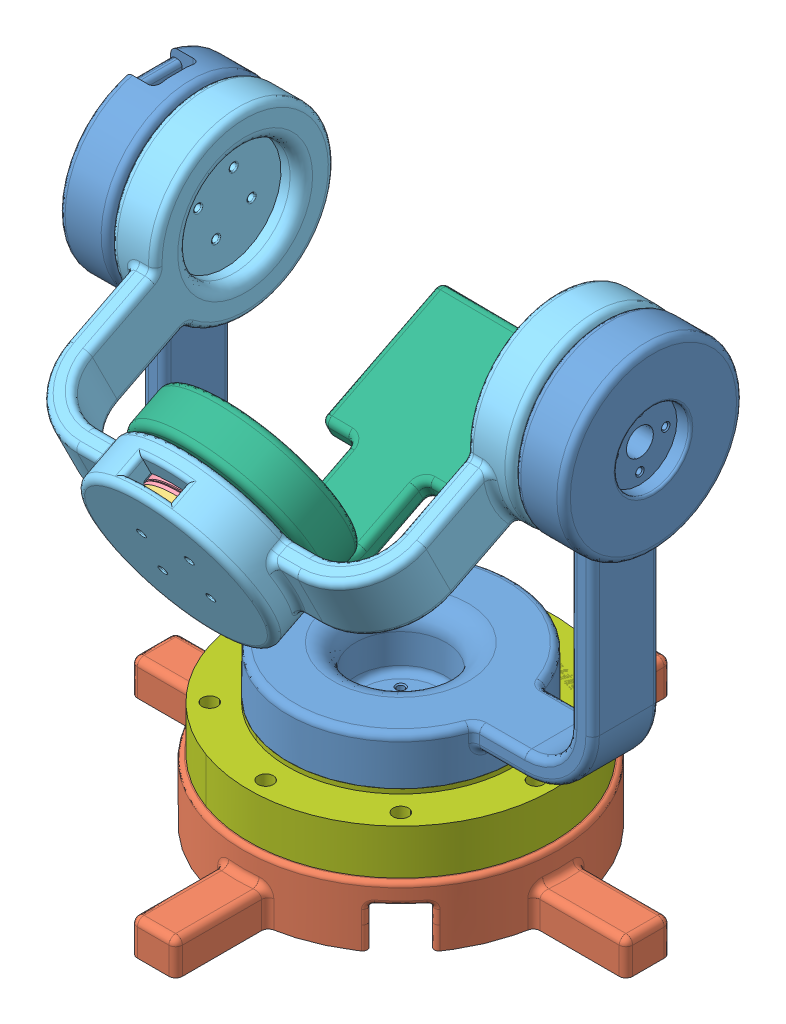
SolidWorks assembly 三轴转台, configuration 默认. Lengths in mm.
Overall size (300.48 271.26 300.48).
11 component instances, 7 part files, 26 mates.
Components (placement in the parent):
- 第一连接臂-1: 第一连接臂 [默认] at (-199.9775 0.5384 135.9766) x (-0.705804 0 0.708407) z (-0.708407 0 -0.705804) size (212.48 206 212.48)
- 转台底座-1: 转台底座 [默认] at (-199.9775 -45.4616 135.9766) size (220 27 220)
- 电机后盖.STEP-2: 电机后盖.STEP [默认] at (-306.9773 144.5384 136.1736) x (0.999998 0 -0.001841) z (0.001841 0 0.999998) size (7 49 49)
- 电机转子.STEP-2: 电机转子.STEP [默认] at (-282.9774 144.5384 136.1294) x (-0.999998 0 0.001841) z (-0.000828 -0.892998 -0.450059) size (19 49 49)
- 第二连接臂-1: 第二连接臂 [默认] at (-282.9774 144.5384 136.1294) x (0.000576 -0.949686 0.313204) z (0.001748 0.313204 0.949684) size (146.24 178 146.24)
- 电机后盖.STEP-3: 电机后盖.STEP [默认] at (-199.8016 96.3819 231.5273) x (-0.001644 0.45006 -0.892997) z (0.661169 -0.66947 -0.338622) size (7 49 49)
- 电机转子.STEP-3: 电机转子.STEP [默认] at (-199.8411 107.1834 210.0953) x (0.001644 -0.45006 0.892997) z (-0.99954 0.026307 0.015098) size (19 49 49)
- 第三连接臂-1: 第三连接臂 [默认] at (-199.8411 107.1834 210.0953) x (-0.728198 -0.612569 -0.307388) z (0.685365 -0.649773 -0.32874) size (102.4 119 102.4)
- 3264716736010.10.100(1).step-1: 3264716736010.10.100(1).step [默认] at (-199.9775 -28.4616 135.9766) x (0.939693 0 0.34202) z (-0.34202 0 0.939693) size (135 22 135)
- 电机后盖.STEP-4: 电机后盖.STEP [默认] at (-199.9775 -45.4616 135.9766) x (0 1 0) z (0.707107 0 -0.707107) size (7 49 49)
- 电机转子.STEP-4: 电机转子.STEP [默认] at (-199.9775 -21.4616 135.9766) x (0 -1 0) z (0.999998 0 -0.001841) size (19 49 49)
Mates (geometry in assembly coordinates):
- 重合9: coincident anti-aligned: plane of 第一连接臂-1 through (-306.9773 0.5384 136.1736) normal (0.999998 0 -0.001841); plane of 电机后盖.STEP-2 through (-306.9773 154.2384 136.1736) normal (-0.999998 0 0.001841)
- 同心7: concentric aligned: cylinder of 第一连接臂-1 through (-306.9773 144.5384 136.1736) axis (0.999998 0 -0.001841) radius 25; cylinder of 电机后盖.STEP-2 through (-299.1523 144.5384 136.1592) axis (0.999998 0 -0.001841) radius 22.5
- 平行4: parallel: line of 第一连接臂-1 through (-302.9589 168.5384 146.1662) axis (0 1 0); plane of 电机后盖.STEP-2 through (-300.9681 171.6257 141.1625) normal (-0.001841 0 -0.999998)
- 重合11: coincident anti-aligned: plane of 电机后盖.STEP-2 through (-299.9773 168.0384 136.1607) normal (0.999998 0 -0.001841); plane of 电机转子.STEP-2 through (-300.016 155.1148 115.1753) normal (-0.999998 0 0.001841)
- 同心8: concentric aligned: cylinder of 电机后盖.STEP-2 through (-299.1523 144.5384 136.1592) axis (0.999998 0 -0.001841) radius 22.5; cylinder of 电机转子.STEP-2 through (-278.5781 144.5384 136.1213) axis (0.999998 0 -0.001841) radius 24.5
- 重合13: coincident anti-aligned: plane of 电机转子.STEP-2 through (-282.9877 147.3738 130.5035) normal (0.999998 0 -0.001841); plane of 第二连接臂-1 through (-282.9774 144.5384 136.1294) normal (-0.999998 0 0.001841)
- 同心11: concentric anti-aligned: cylinder of 电机转子.STEP-2 through (-285.9555 148.4534 148.006) axis (0.999998 0 -0.001841) radius 1.25; cylinder of 第二连接臂-1 through (-272.9555 148.4534 147.982) axis (-0.999998 0 0.001841) radius 1.6
- 同心12: concentric anti-aligned: cylinder of 电机转子.STEP-2 through (-285.9992 140.6233 124.2639) axis (0.999998 0 -0.001841) radius 1.25; cylinder of 第二连接臂-1 through (-272.9992 140.6233 124.2399) axis (-0.999998 0 0.001841) radius 1.6
- 重合14: coincident anti-aligned: plane of 第二连接臂-1 through (-282.8015 96.3819 231.68) normal (-0.001644 0.45006 -0.892997); plane of 电机后盖.STEP-3 through (-192.5244 102.1144 234.403) normal (0.001644 -0.45006 0.892997)
- 同心13: concentric aligned: circle of 第二连接臂-1; circle of 电机后盖.STEP-3
- 重合16: coincident anti-aligned: plane of 电机后盖.STEP-3 through (-182.1826 113.4204 232.2432) normal (-0.001644 0.45006 -0.892997); plane of 电机转子.STEP-3 through (-199.1014 120.5087 235.8468) normal (0.001644 -0.45006 0.892997)
- 同心14: concentric aligned: circle of 电机后盖.STEP-3; cylinder of 电机转子.STEP-3 through (-199.8483 109.1633 206.1668) axis (-0.001644 0.45006 -0.892997) radius 24.5
- 重合17: coincident anti-aligned: plane of 电机转子.STEP-3 through (-199.6503 112.8068 212.9291) normal (-0.001644 0.45006 -0.892997); plane of 第三连接臂-1 through (-199.8411 107.1834 210.0953) normal (0.001644 -0.45006 0.892997)
- 同心15: concentric anti-aligned: cylinder of 电机转子.STEP-3 through (-191.2691 97.711 208.6651) axis (-0.001644 0.45006 -0.892997) radius 1.25; cylinder of 第三连接臂-1 through (-191.2905 103.5618 197.0561) axis (0.001644 -0.45006 0.892997) radius 1.6
- 同心16: concentric anti-aligned: cylinder of 电机转子.STEP-3 through (-208.4032 113.9554 216.8836) axis (-0.001644 0.45006 -0.892997) radius 1.25; cylinder of 第三连接臂-1 through (-208.4246 119.8061 205.2746) axis (0.001644 -0.45006 0.892997) radius 1.6
- 重合18: coincident anti-aligned: plane of 转台底座-1 through (-199.9775 -28.4616 105.9766) normal (0 1 0); plane of 3264716736010.10.100(1).step-1 through (-263.4068 -28.4616 112.8903) normal (0 -1 0)
- 同心18: concentric aligned: cylinder of 转台底座-1 through (-199.9775 -37.4616 195.9766) axis (0 1 0) radius 4; cylinder of 3264716736010.10.100(1).step-1 through (-199.9775 -8.4616 195.9766) axis (0 1 0) radius 3.4
- 同心19: concentric aligned: cylinder of 转台底座-1 through (-157.5511 -37.4616 93.5502) axis (0 1 0) radius 4; cylinder of 3264716736010.10.100(1).step-1 through (-157.5511 -8.4616 93.5502) axis (0 1 0) radius 3.4
- 重合19: coincident anti-aligned: plane of 转台底座-1 through (-199.9775 -45.4616 135.9766) normal (0 1 0); plane of 电机后盖.STEP-4 through (-193.1186 -45.4616 142.8356) normal (0 -1 0)
- 同心21: concentric anti-aligned: cylinder of 3264716736010.10.100(1).step-1 through (-199.9775 -28.4616 135.9766) axis (0 -1 0) radius 32.5; cylinder of 电机后盖.STEP-4 through (-199.9775 -37.6365 135.9766) axis (0 1 0) radius 24.5
- 平行6: parallel aligned: plane of 转台底座-1 through (-124.3171 -40.4616 197.4949) normal (-0.707107 0 0.707107); plane of 电机后盖.STEP-4 through (-177.2884 -39.4616 151.5947) normal (-0.707107 0 0.707107)
- 重合21: coincident anti-aligned: plane of 电机后盖.STEP-4 through (-183.3605 -38.4616 152.5936) normal (0 1 0); plane of 电机转子.STEP-4 through (-200.0208 -38.4616 112.4767) normal (0 -1 0)
- 同心22: concentric aligned: cylinder of 电机后盖.STEP-4 through (-199.9775 -37.6365 135.9766) axis (0 1 0) radius 22.5; cylinder of 电机转子.STEP-4 through (-199.9775 -17.0624 135.9766) axis (0 1 0) radius 24.5
- 同心23: concentric aligned: cylinder of 第一连接臂-1 through (-208.8001 -93.4616 144.8317) axis (0 1 0) radius 1.6; cylinder of 电机转子.STEP-4 through (-208.8001 -24.4616 144.8317) axis (0 1 0) radius 1.25
- 重合22: coincident anti-aligned: plane of 第一连接臂-1 through (-217.6226 -21.4616 153.6868) normal (0 -1 0); plane of 电机转子.STEP-4 through (-199.9891 -21.4616 129.6766) normal (0 1 0)
- 同心25: concentric aligned: cylinder of 第一连接臂-1 through (-191.1224 -93.4616 144.7992) axis (0 1 0) radius 1.6; cylinder of 电机转子.STEP-4 through (-191.1224 -24.4616 144.7992) axis (0 1 0) radius 1.25
